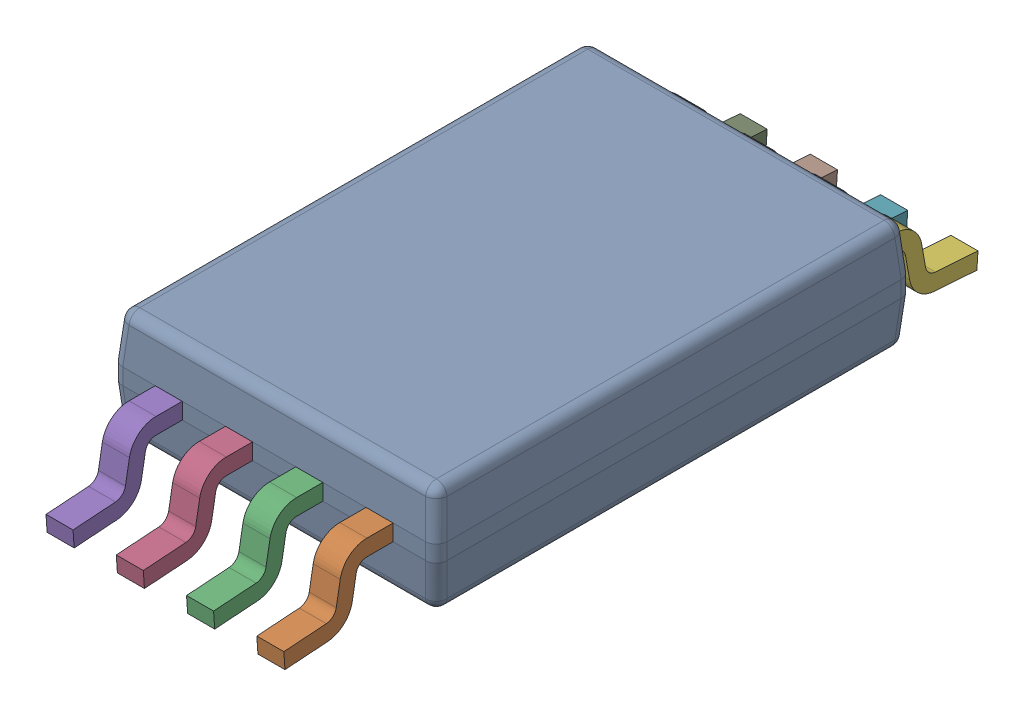
SolidWorks assembly PW0008A, configuration ﾃﾞﾌｫﾙﾄ. Lengths in mm.
Overall size (3 1.12 6.42).
9 component instances, 2 part files, 0 mates.
Components (placement in the parent):
- BODY-SO-1: BODY-SO [ﾃﾞﾌｫﾙﾄ] at origin size (3 1.03 4.4)
- LEAD-SO-1: LEAD-SO [ﾃﾞﾌｫﾙﾄ] at (0.975 -0.425 2.575) size (0.25 0.68 1.01)
- LEAD-SO-2: LEAD-SO [ﾃﾞﾌｫﾙﾄ] at (0.325 -0.425 2.575) size (0.25 0.68 1.01)
- LEAD-SO-3: LEAD-SO [ﾃﾞﾌｫﾙﾄ] at (-0.325 -0.425 2.575) size (0.25 0.68 1.01)
- LEAD-SO-4: LEAD-SO [ﾃﾞﾌｫﾙﾄ] at (-0.975 -0.425 2.575) size (0.25 0.68 1.01)
- LEAD-SO-5: LEAD-SO [ﾃﾞﾌｫﾙﾄ] at (0.975 -0.425 -2.575) x (-1 0 0) z (0 0 -1) size (0.25 0.68 1.01)
- LEAD-SO-6: LEAD-SO [ﾃﾞﾌｫﾙﾄ] at (0.325 -0.425 -2.575) x (-1 0 0) z (0 0 -1) size (0.25 0.68 1.01)
- LEAD-SO-7: LEAD-SO [ﾃﾞﾌｫﾙﾄ] at (-0.325 -0.425 -2.575) x (-1 0 0) z (0 0 -1) size (0.25 0.68 1.01)
- LEAD-SO-8: LEAD-SO [ﾃﾞﾌｫﾙﾄ] at (-0.975 -0.425 -2.575) x (-1 0 0) z (0 0 -1) size (0.25 0.68 1.01)
